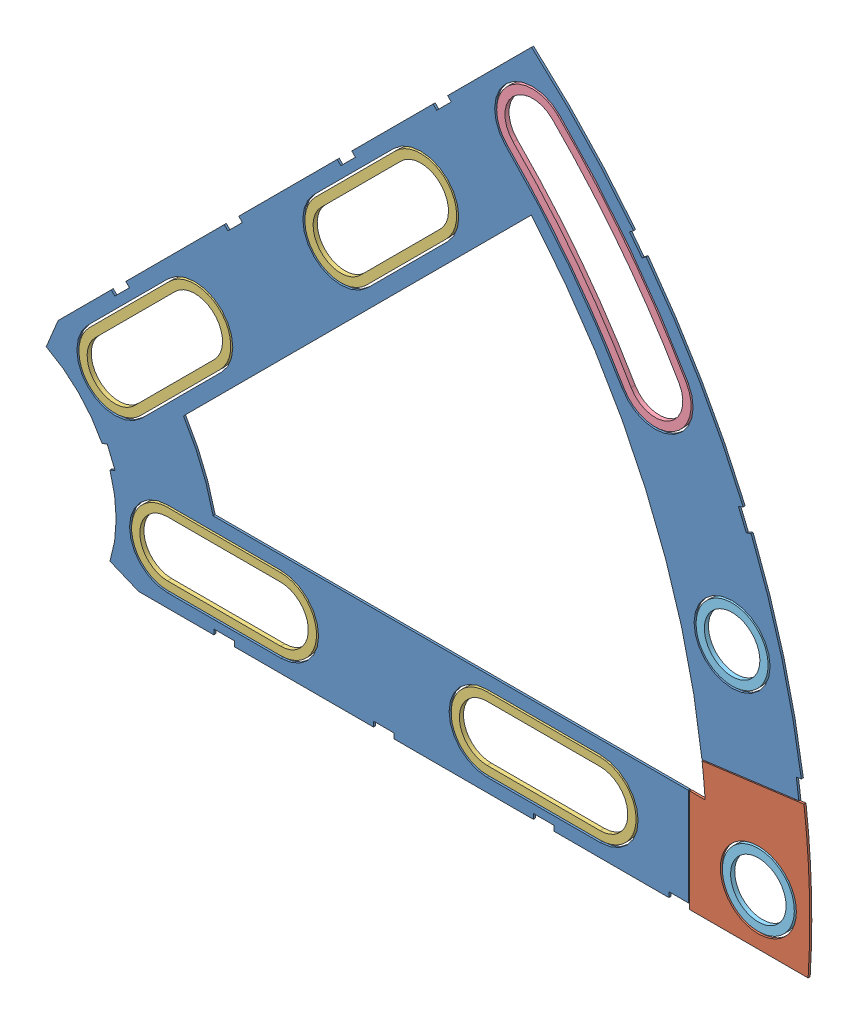
SolidWorks assembly Clover_8_Insul+Pass, configuration Default. Lengths in mm.
Overall size (94.37 82.54 0.51).
9 component instances, 5 part files, 22 mates.
Components (placement in the parent):
- Clover_8_Insul-1: Clover_8_Insul [Default] at (-14.0785 16.2247 67.2248) size (93.33 82.54 0.25)
- Clover_8_Pass-1: Clover_8_Pass [Default] at (-14.0785 16.2247 67.2248) size (14.86 18.35 0.25)
- Clover_Short_Washer-1: Clover_Short_Washer [Default] at (6.576 36.8793 67.4788) x (0.707107 0.707107 0) z (-0.707107 0.707107 0) size (22.86 0.51 8.89)
- Clover_Short_Washer-2: Clover_Short_Washer [Default] at (34.5046 64.8079 67.4788) x (0.707107 0.707107 0) z (-0.707107 0.707107 0) size (22.86 0.51 8.89)
- Clover_Short_Washer-3: Clover_Short_Washer [Default] at (15.1315 16.2247 67.4788) x (1 0 0) z (0 1 0) size (22.86 0.51 8.89)
- Clover_Short_Washer-4: Clover_Short_Washer [Default] at (54.6285 16.2247 67.4788) x (1 0 0) z (0 1 0) size (22.86 0.51 8.89)
- Clover_Outside_Washer-1: Clover_Outside_Washer [Default] at (-14.0785 16.2247 67.4788) x (0.707107 0.707107 0) z (-0.707107 0.707107 0) size (12.14 0.51 33.54)
- Round_Washer-1: Round_Washer [Default] at (77.9259 40.8772 67.4788) x (1 0 0) z (0 1 0) size (8.89 0.51 8.89)
- Round_Washer-2: Round_Washer [Default] at (81.1715 16.2247 67.4788) x (1 0 0) z (0 1 0) size (8.89 0.51 8.89)
Mates (geometry in assembly coordinates):
- Coincident1: coincident: plane of Clover_8_Insul-1 through (-14.0785 16.2247 67.4788) normal (0 0 1); plane of Clover_8_Pass-1 through (-14.0785 16.2247 67.4788) normal (0 0 1)
- Concentric1: concentric: cylinder of Clover_8_Insul-1 through (-14.0785 16.2247 67.4788) axis (0 0 -1) radius 101.6; cylinder of Clover_8_Pass-1 through (-14.0785 16.2247 67.4788) axis (0 0 -1) radius 101.6
- Coincident2: coincident: plane of Clover_8_Insul-1 through (74.5944 22.5747 67.4788) normal (0 1 0); plane of Clover_8_Pass-1 through (74.5944 22.5747 67.4788) normal (0 1 0)
- Concentric2: concentric: circle of Clover_8_Pass-1; circle of Round_Washer-2
- Coincident3: coincident: plane of Clover_8_Pass-1 through (-14.0785 16.2247 67.4788) normal (0 0 1); plane of Round_Washer-2 through (81.1715 16.2247 67.4788) normal (0 0 1)
- Concentric3: concentric: circle of Clover_8_Insul-1; circle of Round_Washer-1
- Coincident4: coincident: plane of Clover_8_Insul-1 through (-14.0785 16.2247 67.4788) normal (0 0 1); plane of Round_Washer-1 through (77.9259 40.8772 67.4788) normal (0 0 1)
- Concentric4: concentric: circle of Clover_8_Insul-1; circle of Clover_Outside_Washer-1
- Concentric5: concentric: circle of Clover_8_Insul-1; circle of Clover_Outside_Washer-1
- Coincident5: coincident: plane of Clover_8_Insul-1 through (-14.0785 16.2247 67.4788) normal (0 0 1); plane of Clover_Outside_Washer-1 through (19.5974 49.9007 67.4788) normal (0 0 1)
- Concentric6: concentric: circle of Clover_8_Insul-1; circle of Clover_Short_Washer-2
- Concentric7: concentric: circle of Clover_8_Insul-1; circle of Clover_Short_Washer-2
- Coincident6: coincident: plane of Clover_8_Insul-1 through (-14.0785 16.2247 67.4788) normal (0 0 1); plane of Clover_Short_Washer-2 through (29.5655 59.8688 67.4788) normal (0 0 1)
- Concentric8: concentric: circle of Clover_8_Insul-1; circle of Clover_Short_Washer-1
- Concentric9: concentric: circle of Clover_8_Insul-1; circle of Clover_Short_Washer-1
- Coincident7: coincident: plane of Clover_8_Insul-1 through (-14.0785 16.2247 67.4788) normal (0 0 1); plane of Clover_Short_Washer-1 through (1.6369 31.9402 67.4788) normal (0 0 1)
- Concentric10: concentric: circle of Clover_8_Insul-1; circle of Clover_Short_Washer-3
- Concentric11: concentric: circle of Clover_8_Insul-1; circle of Clover_Short_Washer-3
- Coincident8: coincident: plane of Clover_8_Insul-1 through (-14.0785 16.2247 67.4788) normal (0 0 1); plane of Clover_Short_Washer-3 through (8.1465 16.2247 67.4788) normal (0 0 1)
- Concentric12: concentric: circle of Clover_8_Insul-1; circle of Clover_Short_Washer-4
- Concentric13: concentric: circle of Clover_8_Insul-1; circle of Clover_Short_Washer-4
- Coincident9: coincident: plane of Clover_8_Insul-1 through (-14.0785 16.2247 67.4788) normal (0 0 1); plane of Clover_Short_Washer-4 through (47.6435 16.2247 67.4788) normal (0 0 1)
